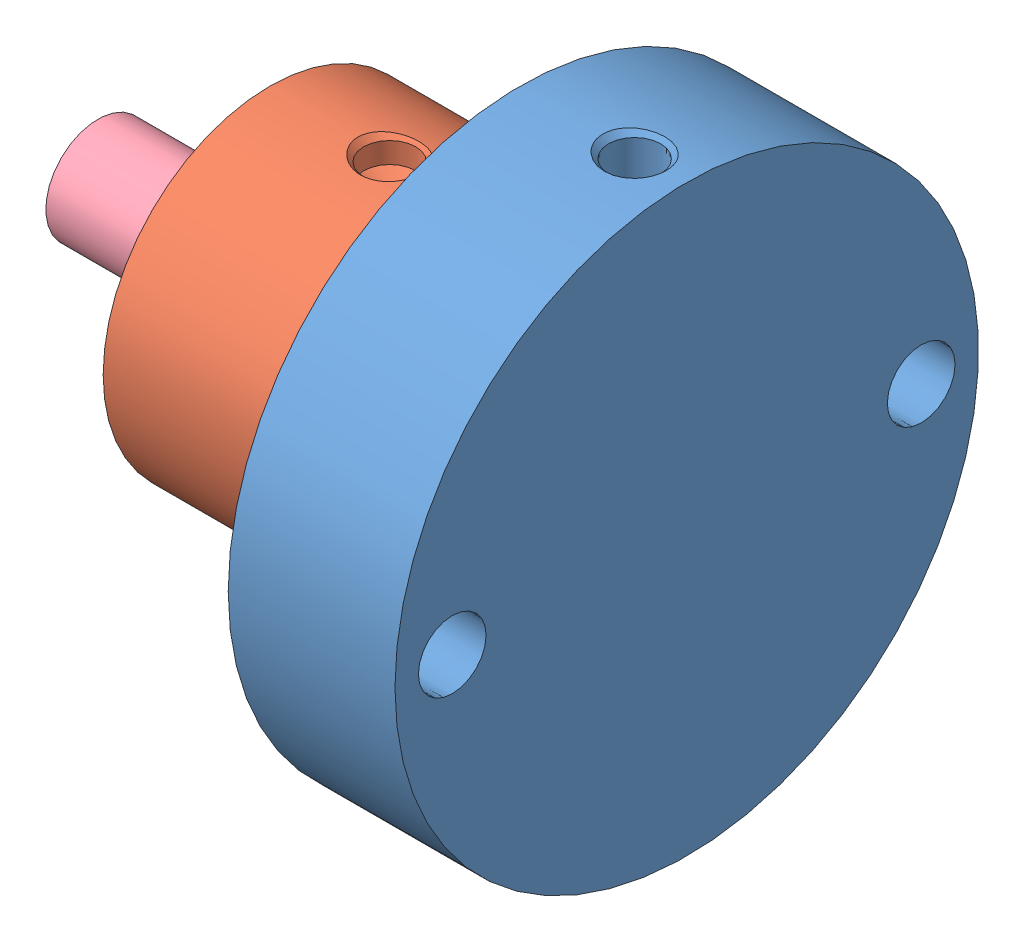
SolidWorks assembly SS-075x1_2-FB, configuration Default. Lengths in mm.
Overall size (44.85 44.45 44.45).
4 component instances, 4 part files, 6 mates.
Components (placement in the parent):
- _SS-075x0.5_body-1: _SS-075x0.5_body [Default] at (0 -3.6178 -29.1734) size (12.7 44.45 44.45)
- _SS-075x0.5_tube-1: _SS-075x0.5_tube [Default] at (0 -3.6178 -29.1734) size (26.82 25.4 25.4)
- _SS-075x0.5_ring-1: _SS-075x0.5_ring [Default] at (-17.907 -3.6178 -29.1734) x (0 0 -1) z (-1 0 0) size (24.38 24.02 0.57)
- _SS-075x0.5_rod-1: _SS-075x0.5_rod [Default] at (-12.7 -3.6178 -29.1734) x (1 0 0) z (0 -0.999668 -0.025772) size (27.21 20.32 20.32)
Mates (geometry in assembly coordinates):
- Concentric1: concentric aligned: cylinder of _SS-075x0.5_tube-1 through (7.766 -3.6178 -29.1734) axis (-1 0 0) radius 4.0958; cylinder of _SS-075x0.5_rod-1 through (-4.934 -3.6178 -29.1734) axis (-1 0 0) radius 3.9688
- Concentric2: concentric aligned: cylinder of _SS-075x0.5_body-1 through (12.7 -3.6178 -29.1734) axis (-1 0 0) radius 22.225; cylinder of _SS-075x0.5_tube-1 through (7.766 -3.6178 -29.1734) axis (-1 0 0) radius 12.7
- Concentric3: concentric aligned: cylinder of _SS-075x0.5_tube-1 through (7.766 -3.6178 -29.1734) axis (-1 0 0) radius 12.7; cylinder of _SS-075x0.5_ring-1 through (-18.4785 -3.6178 -29.1734) axis (-1 0 0) radius 12.192
- Coincident1: coincident anti-aligned: plane of _SS-075x0.5_tube-1 through (-17.907 8.5742 -29.1734) normal (-1 0 0); plane of _SS-075x0.5_ring-1 through (-17.907 -14.6831 -26.3093) normal (1 0 0)
- Coincident3: coincident anti-aligned: plane of _SS-075x0.5_body-1 through (7.766 6.0342 -29.1734) normal (-1 0 0); plane of _SS-075x0.5_tube-1 through (7.766 6.5422 -29.1734) normal (1 0 0)
- LimitDistance1: limit distance = 12.7 mm anti-aligned: plane of _SS-075x0.5_rod-1 through (-4.934 -3.8796 -19.0168) normal (1 0 0); plane of _SS-075x0.5_body-1 through (7.766 6.0342 -29.1734) normal (-1 0 0)
